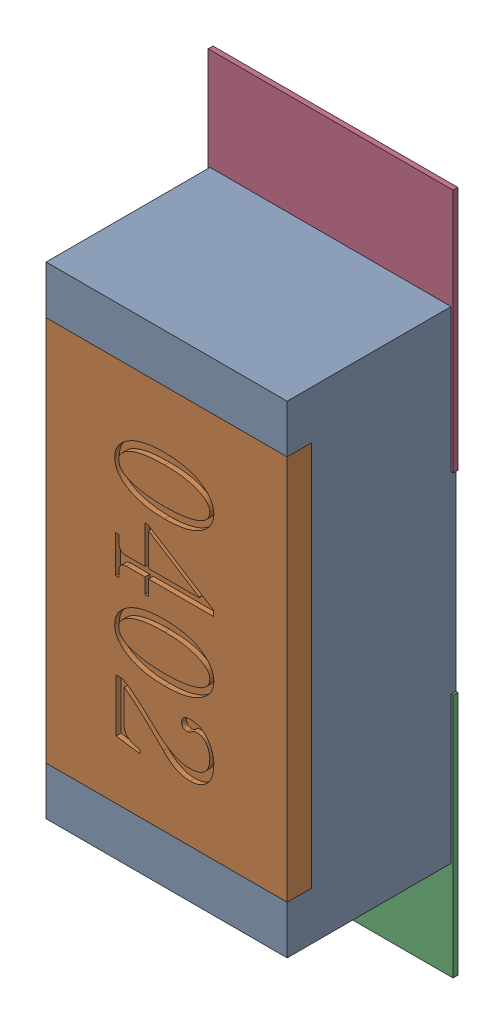
SolidWorks assembly R48, configuration Défaut. Lengths in mm.
Overall size (0.51 1.42 0.35).
5 component instances, 2 part files, 0 mates.
Components (placement in the parent):
- R0402-1: R0402 [Défaut] at (33.4771 -8.4908 0) x (0 -1 0) z (0 0 1) size (1 0.5 0.35)
- 6504207776-1: 6504207776 [Défaut] at (33.4772 -8.9408 0) size (0.51 0.51 0.01)
  - Extruded-1: Extruded [Défaut] at origin size (0.51 0.51 0.01)
- 6504207776-2: 6504207776 [Défaut] at (33.4772 -8.0337 0) size (0.51 0.51 0.01)
  - Extruded-1: Extruded [Défaut] at origin size (0.51 0.51 0.01)
